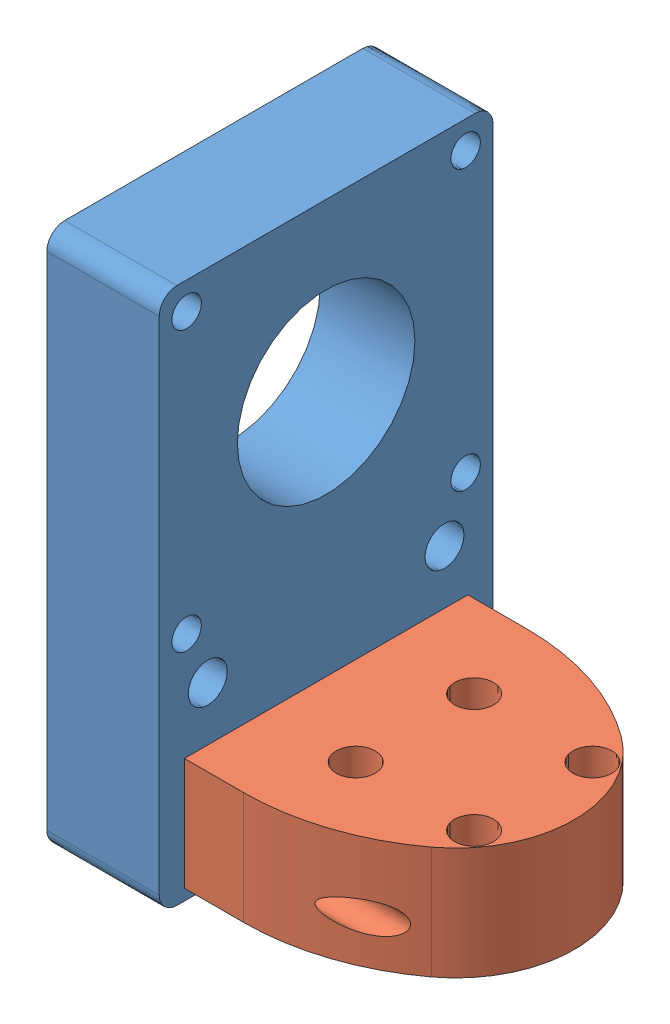
SolidWorks assembly Z motor mount, configuration Default. Lengths in mm.
Overall size (48.59 90.7 87.88).
2 component instances, 2 part files, 3 mates.
Components (placement in the parent):
- z motor mount part A-1: z motor mount part A [Default] at (-19 35.625 23.94) x (0 0 -1) z (1 0 0) size (56.4 90.7 19)
- z motor mount part b-1: z motor mount part b [Default] at (0 35.625 23.94) x (0 0 -1) z (1 0 0) size (87.88 19 48.59)
Mates (geometry in assembly coordinates):
- Coincident1: coincident: plane of assembly; plane of assembly; plane of z motor mount part A-1 through (0 35.625 23.94) normal (1 0 0); plane of z motor mount part b-1 through (0 2.85 47.88) normal (-1 0 0)
- Concentric1: concentric: cylinder of assembly; cylinder of assembly; cylinder of z motor mount part A-1 through (-19 7.3873 43.94) axis (-1 0 0) radius 3.3; cylinder of z motor mount part b-1 through (0 7.3873 43.94) axis (-1 0 0) radius 2.5
- Concentric2: concentric: cylinder of assembly; cylinder of assembly; cylinder of z motor mount part A-1 through (-19 8.125 3.94) axis (-1 0 0) radius 3.3; cylinder of z motor mount part b-1 through (0 8.125 3.94) axis (-1 0 0) radius 2.5
